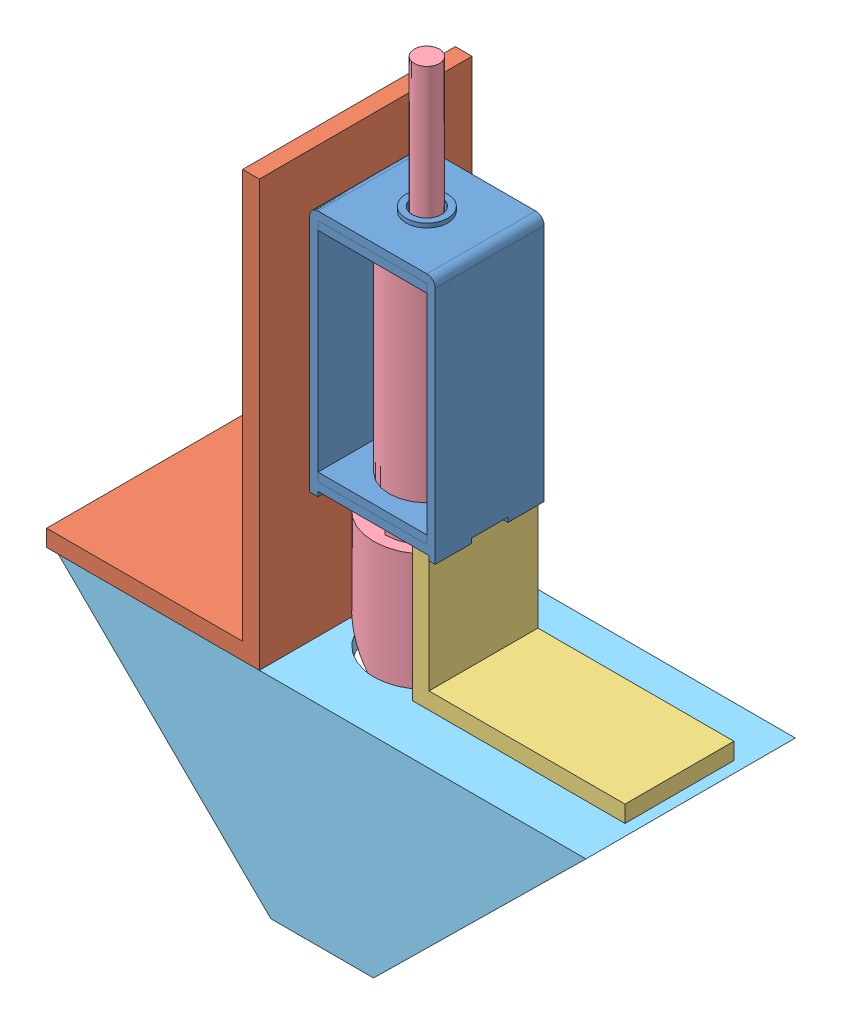
SolidWorks assembly Assem1, configuration Default. Lengths in mm.
Overall size (64.4 86 25.4).
5 component instances, 5 part files, 12 mates.
Components (placement in the parent):
- hold_latch-1: hold_latch [Default] at (9.3394 1.387 23.1203) size (15 30.05 13)
- l1-1: l1 [Default] at (-7.6827 -14.613 23.309) x (0 0 1) z (-1 0 0) size (25.4 50.8 25.4)
- l2-1: l2 [Default] at (15.7018 23.0759 64.2331) x (0 0 1) z (0 1 0) size (13 25.4 16)
- lock-1: lock [Default] at (10.9418 3.387 23.0886) x (0 0 1) z (-1 0 0) size (12.7 66.54 10)
- trunc_base-1: trunc_base [Default] at (-3.2079 -30.5708 10.5886) x (1 0 0) z (0 -1 0) size (63 25 25)
Mates (geometry in assembly coordinates):
- Parallel1: parallel aligned: plane of hold_latch-1 through (3.4418 2.387 29.5886) normal (0 0 1); plane of trunc_base-1 through (-3.2079 -30.5708 35.5886) normal (0 0 1)
- Coincident2: coincident anti-aligned: plane of l2-1 through (17.7018 -14.613 16.7416) normal (0 -1 0); plane of trunc_base-1 through (-20.5582 -14.613 35.5886) normal (0 1 0)
- Parallel2: parallel aligned: plane of l2-1 through (17.7018 -14.613 29.7416) normal (0 0 1); plane of trunc_base-1 through (-3.2079 -30.5708 35.5886) normal (0 0 1)
- Coincident4: coincident anti-aligned: plane of l2-1 through (15.7018 23.0759 64.3861) normal (-1 0 0); plane of lock-1 through (15.7018 -0.613 9.8986) normal (1 0 0)
- Coincident5: coincident aligned: plane of l1-1 through (3.4418 -12.613 35.5886) normal (0 0 1); plane of trunc_base-1 through (-3.2079 -30.5708 35.5886) normal (0 0 1)
- Coincident6: coincident anti-aligned: plane of l1-1 through (-7.6827 -14.613 23.309) normal (0 -1 0); plane of trunc_base-1 through (-20.5582 -14.613 35.5886) normal (0 1 0)
- Concentric2: concentric anti-aligned: circle of lock-1; cylinder of trunc_base-1 through (10.9418 -24.613 23.0886) axis (0 1 0) radius 6.35
- Coincident8: coincident anti-aligned: plane of hold_latch-1 through (3.4418 2.387 16.5886) normal (-1 0 0); plane of l1-1 through (3.4418 -12.613 10.1886) normal (1 0 0)
- Coincident9: coincident anti-aligned: plane of hold_latch-1 through (9.3394 1.387 23.1203) normal (0 -1 0); plane of l2-1 through (17.7018 1.387 16.7416) normal (0 1 0)
- Coincident10: coincident anti-aligned: plane of hold_latch-1 through (9.3394 3.387 23.1203) normal (0 1 0); plane of lock-1 through (10.9418 3.387 23.0886) normal (0 -1 0)
- Concentric3: concentric aligned: circle of hold_latch-1; circle of lock-1
- Coincident11: coincident aligned: plane of hold_latch-1 through (3.4418 2.387 29.5886) normal (0 0 1); plane of l2-1 through (17.7018 -14.613 29.5886) normal (0 0 1)
